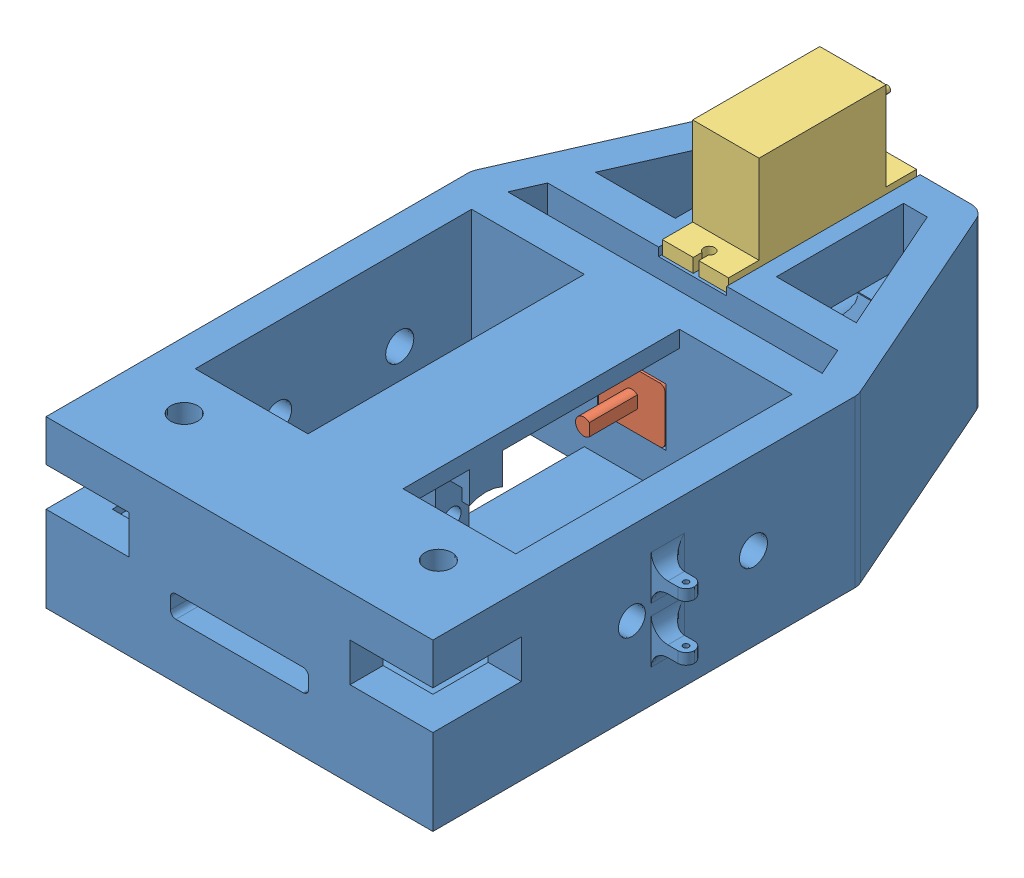
SolidWorks assembly motor_mount, configuration Default. Lengths in mm.
Overall size (82.6 47 117).
3 component instances, 3 part files, 9 mates.
Components (placement in the parent):
- front_body-1: front_body [Default] at (43.5986 45.5272 110.2067) size (82.6 30 117)
- motor-1: motor [Default] at (43.5986 60.3272 50.1067) size (12 10 41.8)
- tg9e_micro_servo-1: tg9e_micro_servo [Default] at (43.5986 92.5272 49.2067) x (0 0 -1) z (-1 0 0) size (34 30 12)
Mates (geometry in assembly coordinates):
- Coincident4: coincident anti-aligned: plane of front_body-1 through (49.7986 55.3272 148.7077) normal (0 1 0); plane of motor-1 through (40.1486 55.3272 65.1067) normal (0 -1 0)
- Coincident5: coincident aligned: plane of front_body-1 through (14.5986 75.5272 77.7067) normal (0 0 1); plane of motor-1 through (43.5986 60.3272 77.7067) normal (0 0 1)
- Distance1: distance = 0.2 mm anti-aligned: plane of motor-1 through (37.5986 65.3272 77.7067) normal (-1 0 0); plane of front_body-1 through (37.3986 65.7272 148.7077) normal (1 0 0)
- Coincident7: coincident anti-aligned: plane of front_body-1 through (43.5986 74.0272 110.2067) normal (0 1 0); plane of tg9e_micro_servo-1 through (49.5986 74.0272 66.2067) normal (0 -1 0)
- Concentric1: concentric anti-aligned: cylinder of front_body-1 through (43.5986 45.5261 34.7067) axis (0 1 0) radius 0.8; cylinder of tg9e_micro_servo-1 through (43.5986 79.0272 34.7067) axis (0 -1 0) radius 1
- Concentric2: concentric anti-aligned: cylinder of front_body-1 through (43.5986 45.5261 63.7067) axis (0 1 0) radius 0.8; cylinder of tg9e_micro_servo-1 through (43.5986 79.0272 63.7067) axis (0 -1 0) radius 1
- Coincident8: coincident anti-aligned: plane of front_body-1 through (54.7986 60.3272 51.7067) normal (1 0 0); plane of ? through (54.7986 60.3272 90.4381) normal (-1 0 0)
- Coincident9: coincident anti-aligned: plane of front_body-1 through (43.5986 45.5272 51.7067) normal (0 0 -1); plane of ? through (43.5986 55.3272 51.7067) normal (0 0 1)
- Coincident10: coincident anti-aligned: plane of front_body-1 through (54.7986 50.3272 51.7067) normal (0 -1 0); plane of ? through (54.7986 50.3272 90.4381) normal (0 1 0)
